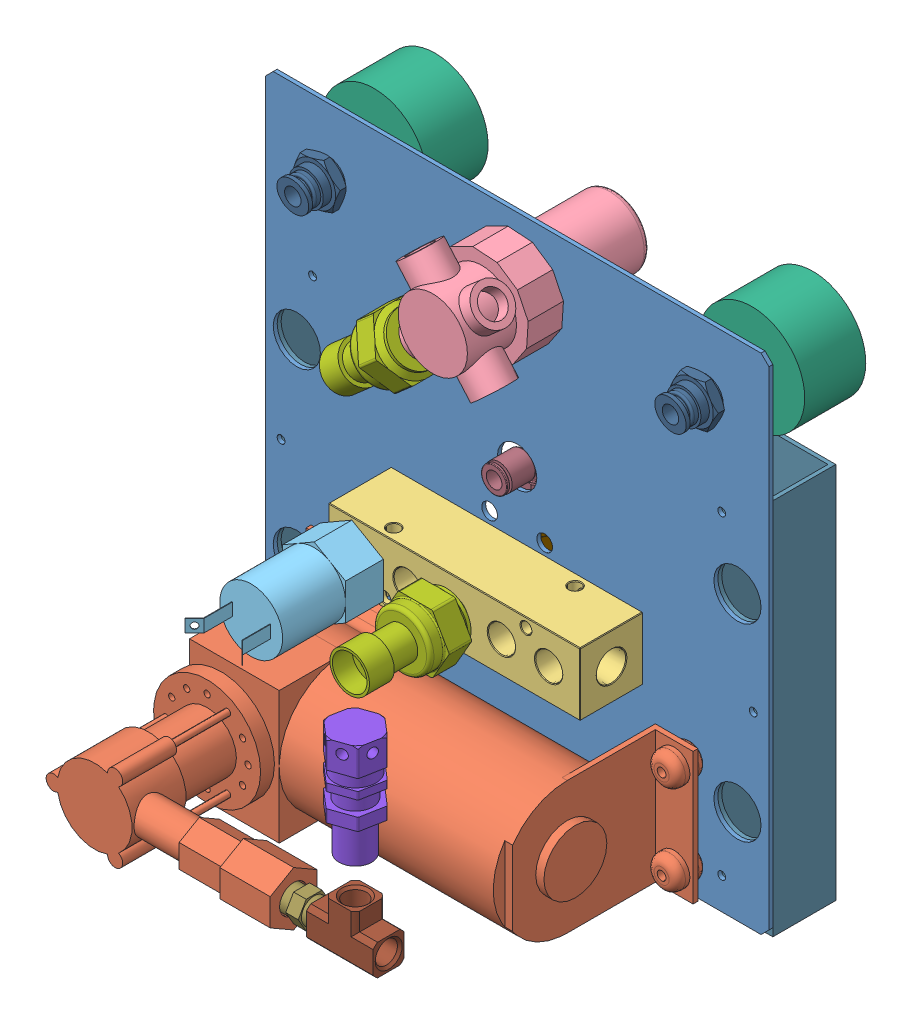
SolidWorks assembly Pneumatics, configuration Default. Lengths in mm.
Overall size (203.2 207.55 167.13).
18 component instances, 14 part files, 39 mates.
Components (placement in the parent):
- Compressor Plate-1: Compressor Plate [Default] at origin size (203.2 203.2 1.59)
- Compressor_90C-1: Compressor_90C [Default] at (101.6 30.734 42.672) x (0 -1 0) z (-1 0 0) size (53.59 121.98 156.21)
- Manifold-1: Manifold [Default] at (101.6 76.2 12.7) x (1 0 0) z (0 -1 0) size (101.6 25.4 25.4)
- PressureRegulator-1: PressureRegulator [Default] at (101.6 177.8 34.036) x (-0.752906 -0.658128 0) z (0.658128 -0.752906 0) size (38.1 73.91 45.72)
- PressureSwitch-1: PressureSwitch [Default] at (63.5 76.2 18.415) x (1 0 0) z (0 -1 0) size (25.4 66.04 29.33)
- PressureGauge-1: PressureGauge [Default] at (177.8 177.8 -43.1419) x (-0.996936 0.078222 0) z (0 0 -1) size (42.67 42.67 40.64)
- REV-11-1107-1: REV-11-1107 [Default] at (101.6 76.2 28.575) x (1 0 0) z (0 -1 0) size (27.11 49 23.75)
- ReliefValve-1: ReliefValve [Default] at (148.844 103.2375 112.522) x (0.982823 0 0.184551) z (-0.184551 0 0.982823) size (17.5 44 20.05)
- Ball Valve-1: Ball Valve [Default] at (101.6 80.1655 -8.6995) x (0 -1 0) z (0 0 -1) size (46.48 16.88 22.61)
- Female Fitting 1_8 NPT 1_4 tube (am-2033)-1: Female Fitting 1_8 NPT 1_4 tube (am-2033) [Default] at (177.8 177.8 0.8318) x (0 0 -1) z (0.890935 -0.454131 0) size (26.99 19.59 16.97)
- UnionTee-1: UnionTee [Default] at (148.844 30.734 112.522) x (1 0 0) z (0 -1 0) size (26.92 12.5 19.71)
- HexNipple_0.125-1: HexNipple_0.125 [Default] at (129.667 30.734 112.522) x (0 0 1) z (-1 0 0) size (12.83 11.11 24.64)
- Female Fitting 1_8 NPT 1_4 tube (am-2033)-2: Female Fitting 1_8 NPT 1_4 tube (am-2033) [Default] at (25.4 177.8 0.8318) x (0 0 -1) z (0.951669 -0.307127 0) size (26.99 19.59 16.97)
- PressureGauge-2: PressureGauge [Default] at (25.4 177.8 -43.1419) x (-0.996728 -0.080834 0) z (0 0 -1) size (42.67 42.67 40.64)
- PrestolokElbowConnector-1: PrestolokElbowConnector [Default] at (101.6 102.708 -8.6995) x (0 0 1) z (-1 0 0) size (23.51 24.52 12)
- REV-11-1107-2: REV-11-1107 [Default] at (84.8667 163.1731 24.13) x (-0.001625 0.001859 -0.999997) z (-0.658126 0.752904 0.002469) size (27.11 49 23.75)
- Pneumatics Square Tube-1: Pneumatics Square Tube [Default] at (190.5 0 -14.2875) size (25.4 152.4 25.4)
- Pneumatics Square Tube-2: Pneumatics Square Tube [Default] at (12.7 152.4 -14.2875) x (-1 0 0) z (0 0 1) size (25.4 152.4 25.4)
Mates (geometry in assembly coordinates):
- Concentric1: concentric anti-aligned: cylinder of Compressor Plate-1 through (31.115 48.768 0) axis (0 0 -1) radius 2.413; cylinder of Compressor_90C-1 through (31.115 48.768 5.08) axis (0 0 1) radius 1.778
- Coincident1: coincident anti-aligned: plane of Compressor Plate-1 through (0 0 0) normal (0 0 1); plane of Compressor_90C-1 through (31.115 30.734 0) normal (0 0 -1)
- Parallel1: parallel aligned: plane of Compressor Plate-1 through (0 0 -1.5875) normal (0 -1 0); plane of Compressor_90C-1 through (40.767 4.064 42.672) normal (0 -1 0)
- Coincident2: coincident anti-aligned: plane of Compressor Plate-1 through (0 0 0) normal (0 0 1); plane of Manifold-1 through (152.4 88.9 0) normal (0 0 -1)
- Distance1: distance = 63.5 mm aligned: plane of Manifold-1 through (152.4 63.5 0) normal (0 -1 0); plane of Compressor Plate-1 through (0 0 -1.5875) normal (0 -1 0)
- Width1: width anti-aligned: plane of Manifold-1 through (50.8 76.2 12.7) normal (-1 0 0); plane of Compressor Plate-1 through (152.4 76.2 12.7) normal (1 0 0); plane of Manifold-1 through (203.2 0 -1.5875) normal (1 0 0); plane of Compressor Plate-1 through (0 0 -1.5875) normal (-1 0 0)
- Concentric3: concentric anti-aligned: cylinder of PressureGauge-1 through (177.8 177.8 -43.1419) axis (0 0 -1) radius 4.699; cone of Female Fitting 1_8 NPT 1_4 tube (am-2033)-1 through (177.8 177.8 -12.6619) axis (0 0 1)
- Coincident3: coincident anti-aligned: plane of PressureGauge-1 through (178.2272 183.2443 -12.6619) normal (0 0 1); plane of Female Fitting 1_8 NPT 1_4 tube (am-2033)-1 through (177.8 177.8 -12.6619) normal (0 0 -1)
- Concentric4: concentric aligned: cylinder of PressureSwitch-1 through (63.5 76.2 28.575) axis (0 0 -1) radius 4.318; cone of Manifold-1 through (63.5 76.2 25.4) axis (0 0 -1)
- Distance2: distance = 3.175 mm anti-aligned: plane of Manifold-1 through (152.4 88.9 25.4) normal (0 0 1); plane of PressureSwitch-1 through (63.5 76.2 28.575) normal (0 0 -1)
- Concentric6: concentric aligned: cone of Manifold-1 through (101.6 76.2 25.4) axis (0 0 -1); cone of REV-11-1107-1 through (101.6 76.2 28.0924) axis (0 0 -1)
- Distance3: distance = 3.175 mm anti-aligned: plane of Manifold-1 through (152.4 88.9 25.4) normal (0 0 1); plane of REV-11-1107-1 through (101.6 76.2 28.575) normal (0 0 -1)
- Concentric7: concentric anti-aligned: cylinder of Compressor_90C-1 through (123.952 30.734 112.522) axis (-1 0 0) radius 5.715; cylinder of HexNipple_0.125-1 through (117.348 30.734 112.522) axis (1 0 0) radius 5.1435
- Distance4: distance = 3.175 mm anti-aligned: plane of Compressor_90C-1 through (123.952 30.734 42.672) normal (1 0 0); plane of HexNipple_0.125-1 through (127.127 30.734 112.522) normal (-1 0 0)
- Concentric8: concentric aligned: cone of UnionTee-1 through (142.2993 30.734 112.522) axis (1 0 0); cylinder of HexNipple_0.125-1 through (117.348 30.734 112.522) axis (1 0 0) radius 5.1435
- Distance5: distance = 3.175 mm anti-aligned: plane of UnionTee-1 through (135.382 30.734 112.522) normal (-1 0 0); plane of HexNipple_0.125-1 through (132.207 30.734 112.522) normal (1 0 0)
- Parallel2: parallel aligned: plane of Compressor Plate-1 through (0 0 0) normal (0 0 1); plane of UnionTee-1 through (148.844 26.2234 118.7704) normal (0 0 1)
- Concentric9: concentric anti-aligned: cylinder of ReliefValve-1 through (148.844 59.2375 112.522) axis (0 1 0) radius 6.625; cone of UnionTee-1 through (148.844 43.2256 112.522) axis (0 -1 0)
- Concentric10: concentric aligned: cylinder of Compressor Plate-1 through (177.8 177.8 0) axis (0 0 -1) radius 6.985; cylinder of Female Fitting 1_8 NPT 1_4 tube (am-2033)-1 through (177.8 177.8 -12.6619) axis (0 0 -1) radius 6.9024
- Coincident4: coincident anti-aligned: plane of Compressor Plate-1 through (0 0 -1.5875) normal (0 0 -1); plane of Female Fitting 1_8 NPT 1_4 tube (am-2033)-1 through (180.9346 183.9496 -1.5875) normal (0 0 1)
- Concentric11: concentric aligned: cylinder of Compressor Plate-1 through (101.6 177.8 0) axis (0 0 -1) radius 13.97; cylinder of PressureRegulator-1 through (101.6 177.8 -39.878) axis (0 0 -1) radius 13.97
- Coincident5: coincident anti-aligned: plane of Compressor Plate-1 through (0 0 0) normal (0 0 1); plane of PressureRegulator-1 through (91.0819 168.606 0) normal (0 0 -1)
- Concentric12: concentric anti-aligned: cone of Female Fitting 1_8 NPT 1_4 tube (am-2033)-2 through (25.4 177.8 -12.6619) axis (0 0 1); cylinder of PressureGauge-2 through (25.4 177.8 -43.1419) axis (0 0 -1) radius 4.699
- Coincident6: coincident anti-aligned: plane of Female Fitting 1_8 NPT 1_4 tube (am-2033)-2 through (25.4 177.8 -12.6619) normal (0 0 -1); plane of PressureGauge-2 through (24.9586 183.2431 -12.6619) normal (0 0 1)
- Concentric13: concentric aligned: cylinder of Compressor Plate-1 through (25.4 177.8 0) axis (0 0 -1) radius 6.985; cylinder of Female Fitting 1_8 NPT 1_4 tube (am-2033)-2 through (25.4 177.8 -12.6619) axis (0 0 -1) radius 6.9024
- Coincident7: coincident anti-aligned: plane of Compressor Plate-1 through (0 0 -1.5875) normal (0 0 -1); plane of Female Fitting 1_8 NPT 1_4 tube (am-2033)-2 through (27.5199 184.3688 -1.5875) normal (0 0 1)
- Coincident9: coincident anti-aligned: plane of Compressor Plate-1 through (0 0 -1.5875) normal (0 0 -1); plane of Ball Valve-1 through (105.7061 60.798 -1.5875) normal (0 0 1)
- Concentric15: concentric aligned: cone of Ball Valve-1 through (101.6 90.389 -8.6995) axis (0 -1 0); cone of PrestolokElbowConnector-1 through (101.6 102.708 -8.6995) axis (0 -1 0)
- Distance6: distance = 3.175 mm anti-aligned: plane of Ball Valve-1 through (101.6 99.533 -8.6995) normal (0 1 0); plane of PrestolokElbowConnector-1 through (101.6 102.708 -8.6995) normal (0 -1 0)
- Concentric16: concentric anti-aligned: cylinder of Compressor Plate-1 through (101.6 114.3 0) axis (0 0 -1) radius 7.9375; cylinder of PrestolokElbowConnector-1 through (101.6 114.3 7.4005) axis (0 0 1) radius 5.425
- Concentric17: concentric aligned: cylinder of PressureRegulator-1 through (84.3886 162.7552 24.13) axis (0.752906 0.658128 0) radius 5.207; cone of REV-11-1107-2 through (85.23 163.4907 24.13) axis (0.752906 0.658128 0)
- Distance7: distance = 3.175 mm anti-aligned: plane of REV-11-1107-2 through (84.8667 163.1731 24.13) normal (0.752906 0.658128 0); plane of PressureRegulator-1 through (87.2571 165.2627 24.13) normal (-0.752906 -0.658128 0)
- Parallel3: parallel aligned: plane of Compressor Plate-1 through (0 0 -1.5875) normal (0 -1 0); plane of Ball Valve-1 through (101.6 60.798 -8.6995) normal (0 -1 0)
- Coincident16: coincident anti-aligned: plane of Compressor Plate-1 through (0 0 -1.5875) normal (0 0 -1); plane of Pneumatics Square Tube-1 through (203.2 152.4 -1.5875) normal (0 0 1)
- Coincident17: coincident aligned: plane of Compressor Plate-1 through (203.2 0 -1.5875) normal (1 0 0); plane of Pneumatics Square Tube-1 through (203.2 152.4 -1.5875) normal (1 0 0)
- Coincident18: coincident aligned: plane of Compressor Plate-1 through (0 0 -1.5875) normal (0 -1 0); plane of Pneumatics Square Tube-1 through (190.5 0 -14.2875) normal (0 -1 0)
- Coincident19: coincident anti-aligned: plane of Compressor Plate-1 through (0 0 -1.5875) normal (0 0 -1); plane of Pneumatics Square Tube-2 through (0 0 -1.5875) normal (0 0 1)
- Coincident22: coincident aligned: plane of Compressor Plate-1 through (0 0 -1.5875) normal (-1 0 0); plane of Pneumatics Square Tube-2 through (0 0 -1.5875) normal (-1 0 0)
- Coincident23: coincident aligned: plane of Compressor Plate-1 through (0 0 -1.5875) normal (0 -1 0); plane of Pneumatics Square Tube-2 through (12.7 0 -14.2875) normal (0 -1 0)
